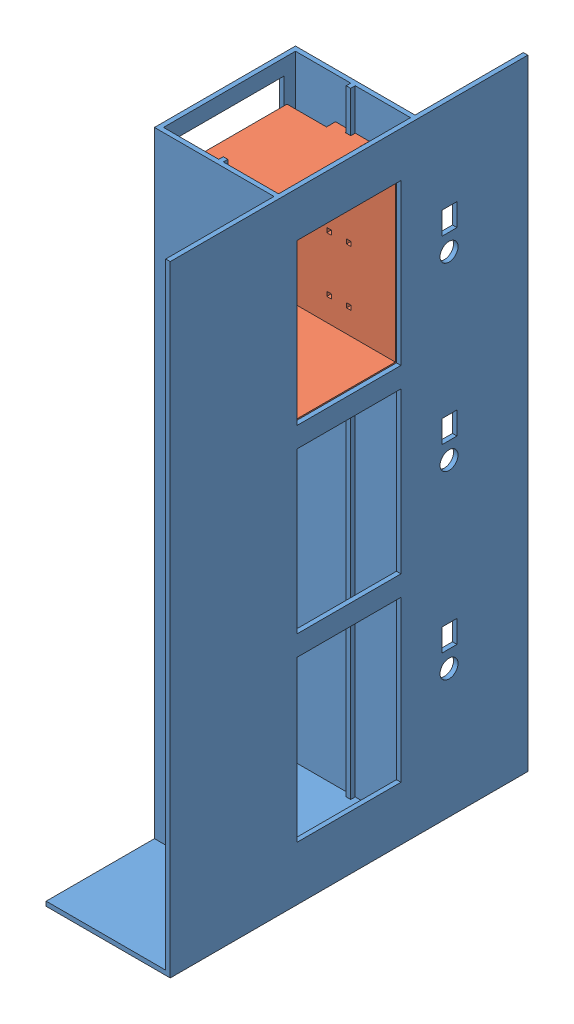
SolidWorks assembly Assemblage1, configuration Défaut. Lengths in mm.
Overall size (110 550 317).
2 component instances, 2 part files, 2 mates.
Components (placement in the parent):
- Pièce2-1: Pièce2 [Défaut] at (80.5874 -236.6496 -532.8395) size (110 550 317)
- Pièce1-2: Pièce1 [Défaut] at (181.5874 123.4598 -520.3395) x (0 0 1) z (-1 0 0) size (116 150 100)
Mates (geometry in assembly coordinates):
- Distance2: distance = 1 mm anti-aligned: plane of Pièce2-1 through (182.5874 -236.6496 -532.8395) normal (-1 0 0); plane of Pièce1-2 through (181.5874 123.4598 -520.3395) normal (1 0 0)
- Distance1: distance = 0.5 mm anti-aligned: plane of Pièce1-2 through (181.5874 123.4598 -416.3395) normal (0 0 1); plane of Pièce2-1 through (80.5874 -236.6496 -415.8395) normal (0 0 -1)
